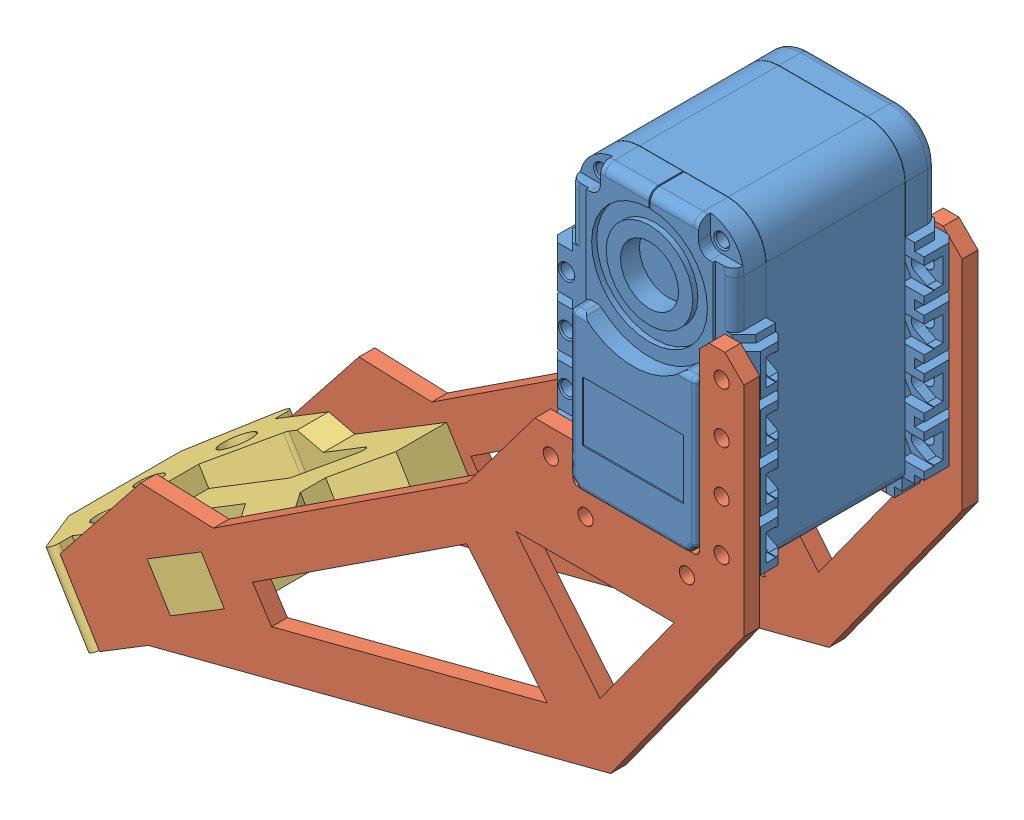
SolidWorks assembly Tibia_left, configuration Default. Lengths in mm.
Overall size (119.5 110.03 38.67).
5 component instances, 4 part files, 12 mates.
Components (placement in the parent):
- ServoBody-1: ServoBody [Default] at origin size (32 50.04 38.67)
- Tibia side plate-1: Tibia side plate [Défaut] at (0.5 -20.25 -31.9) x (0 -1 0) z (0 0 1) size (90.35 108.03 2.5)
- Tibia side plate-2: Tibia side plate [Défaut] at (0.5 -20.25 2.6) x (0 -1 0) z (0 0 1) size (90.35 108.03 2.5)
- Foot-1: Foot [Défaut] at (-65.4223 -77.6675 -13.4) x (0 0 1) z (-0.521616 0.853181 0) size (37.94 40 13)
- RubberFeet-1: RubberFeet [Default] at (-95.4029 -91.8947 -13.4) x (0.521616 -0.853181 0) z (0 0 1) size (9.6 4.8 9.6)
Mates (geometry in assembly coordinates):
- Coincident6: coordinate: point of ServoBody-1; point of assembly
- Concentric1: concentric aligned: cylinder of ServoBody-1 through (14 -30.5 0.6) axis (0 0 1) radius 1.1; cylinder of Tibia side plate-2 through (14 -30.5 5.1) axis (0 0 1) radius 1.2
- Concentric2: concentric aligned: cylinder of ServoBody-1 through (14 -6.5 0.6) axis (0 0 1) radius 1.1; cylinder of Tibia side plate-2 through (14 -6.5 5.1) axis (0 0 1) radius 1.2
- Coincident1: coincident anti-aligned: plane of ServoBody-1 through (-14.996 -38.283 2.6) normal (0 0 1); plane of Tibia side plate-2 through (0.5 -20.25 2.6) normal (0 0 -1)
- Concentric3: concentric aligned: cylinder of ServoBody-1 through (14 -30.5 -29.2) axis (0 0 1) radius 1.1; cylinder of Tibia side plate-1 through (14 -30.5 -29.4) axis (0 0 1) radius 1.2
- Concentric4: concentric aligned: cylinder of ServoBody-1 through (14 -6.5 -29.2) axis (0 0 1) radius 1.1; cylinder of Tibia side plate-1 through (14 -6.5 -29.4) axis (0 0 1) radius 1.2
- Coincident2: coincident anti-aligned: plane of ServoBody-1 through (15.996 -38.348 -29.4) normal (0 0 -1); plane of Tibia side plate-1 through (0.5 -20.25 -29.4) normal (0 0 1)
- Coincident3: coincident anti-aligned: plane of Tibia side plate-2 through (0.5 -20.25 2.6) normal (0 0 -1); plane of Foot-1 through (-69.0736 -71.6952 2.6) normal (0 0 1)
- Coincident4: coincident anti-aligned: plane of Tibia side plate-2 through (-68.2204 -71.1736 2.599) normal (-0.853181 -0.521616 0); plane of Foot-1 through (-68.2204 -71.1736 -13.4) normal (0.853181 0.521616 0)
- Coincident5: coincident anti-aligned: plane of Tibia side plate-2 through (-68.2204 -71.1736 2.599) normal (0.521616 -0.853181 0); plane of Foot-1 through (-69.0736 -71.6952 -13.4) normal (-0.521616 0.853181 0)
- Coincident7: coincident anti-aligned: plane of Foot-1 through (-95.4029 -91.8947 -13.4) normal (-0.853181 -0.521616 0); plane of RubberFeet-1 through (-97.9066 -87.7994 -13.4) normal (0.853181 0.521616 0)
- Coincident8: coincident anti-aligned: circle of Foot-1; circle of RubberFeet-1
